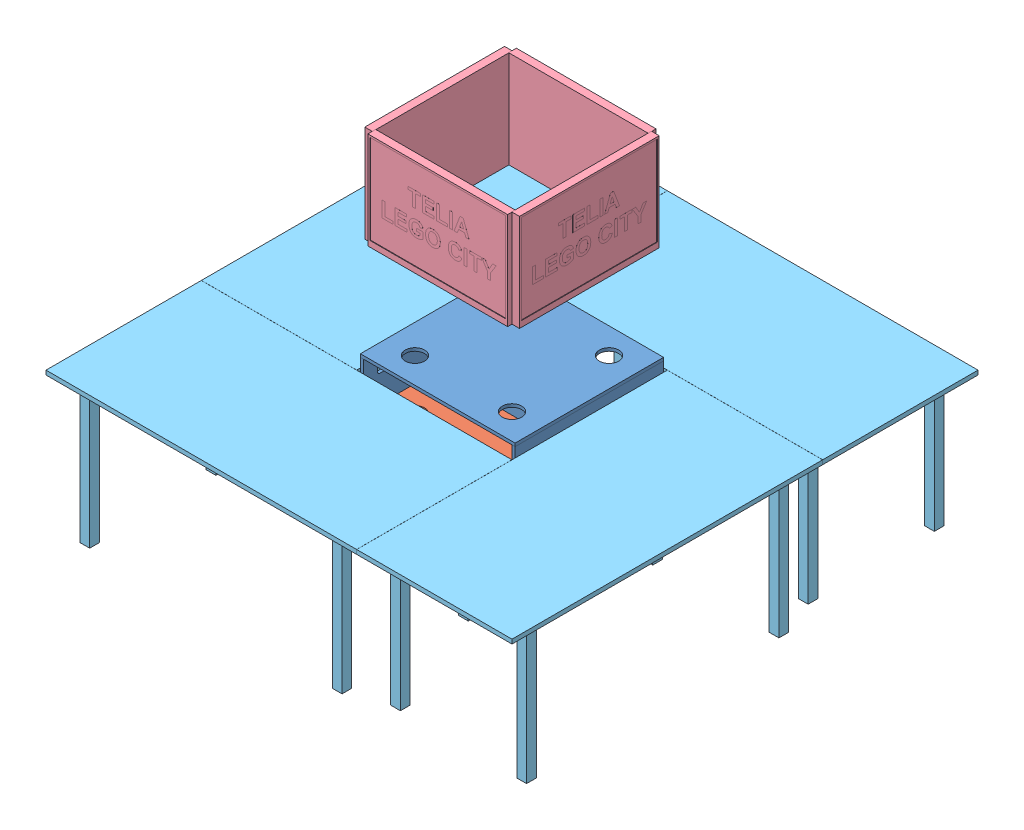
SolidWorks assembly bottom-assembly, configuration Default. Lengths in mm.
Overall size (2400.5 1797 2400.5).
16 component instances, 5 part files, 44 mates.
Components (placement in the parent):
- table-board-1: table-board [Side boards] at (59.7542 3.6875 0) x (0 -1 0) z (0 0 1) size (765 16 765)
- table-board-2: table-board [Middle board] at (458.2542 3.6875 -8) x (1 0 0) z (0 -1 0) size (765 16 765)
- table-board-3: table-board [Side boards] at (840.7542 3.6875 0) x (0 -1 0) z (0 0 1) size (765 16 765)
- table-board-4: table-board [Wide with holes] at (474.2542 386.1875 0) size (797 16 765)
- table-board-5: table-board [Wide] at (474.2542 -394.8125 0) size (797 16 765)
- table-shelf-1: table-shelf [WIth holes] at (458.2542 -136.58 195.25) size (765 16 374.5)
- computer-1: computer [Default] at (446.7489 -378.8125 -241.6898) x (-1 0 0) z (0 0 -1) size (490 460 190)
- table-shelf-2: table-shelf [WIth holes] at (458.2542 127.9549 195.25) size (765 16 374.5)
- tv-1: tv [Default] at (458.2542 1152.1875 342.5) x (1 0 0) z (0 -1 0) size (720 40 500)
- tv-3: tv [Default] at (816.7542 1152.1875 0) x (0 0 -1) z (0 -1 0) size (720 40 500)
- tv-5: tv [Default] at (458.2542 1152.1875 -342.5) x (-1 0 0) z (0 -1 0) size (720 40 500)
- tv-7: tv [Default] at (99.7542 1152.1875 0) x (0 0 1) z (0 -1 0) size (720 40 500)
- table-section-1: table-section [Default] at (-341.9958 315.1875 -400.25) x (0 0 1) z (-1 0 0) size (1600 732 800)
- table-section-2: table-section [Default] at (58.0042 315.1875 800.25) size (1600 732 800)
- table-section-4: table-section [Default] at (1258.5042 315.1875 400.25) x (0 0 -1) z (1 0 0) size (1600 732 800)
- table-section-5: table-section [Default] at (858.5042 315.1875 -800.25) x (-1 0 0) z (0 0 -1) size (1600 732 800)
Mates (geometry in assembly coordinates):
- Coincident5: coincident aligned: plane of table-board-2 through (75.7542 386.1875 8) normal (0 1 0); plane of table-board-3 through (856.7542 386.1875 -382.5) normal (0 1 0)
- Coincident8: coincident anti-aligned: plane of table-board-2 through (840.7542 386.1875 8) normal (1 0 0); plane of table-board-3 through (840.7542 3.6875 0) normal (-1 0 0)
- Coincident9: coincident anti-aligned: plane of table-board-2 through (75.7542 386.1875 8) normal (0 1 0); plane of table-board-4 through (474.2542 386.1875 0) normal (0 -1 0)
- Coincident10: coincident aligned: plane of table-board-3 through (856.7542 3.6875 0) normal (1 0 0); plane of table-board-4 through (856.7542 402.1875 -382.5) normal (1 0 0)
- Coincident11: coincident aligned: plane of table-board-3 through (856.7542 386.1875 382.5) normal (0 0 1); plane of table-board-4 through (91.7542 402.1875 382.5) normal (0 0 1)
- Coincident12: coincident anti-aligned: plane of table-board-2 through (75.7542 -378.8125 8) normal (0 -1 0); plane of table-board-5 through (474.2542 -378.8125 0) normal (0 1 0)
- Coincident13: coincident aligned: plane of table-board-3 through (856.7542 386.1875 382.5) normal (0 0 1); plane of table-board-5 through (91.7542 -378.8125 382.5) normal (0 0 1)
- Coincident14: coincident aligned: plane of table-board-3 through (856.7542 3.6875 0) normal (1 0 0); plane of table-board-5 through (856.7542 -378.8125 -382.5) normal (1 0 0)
- Coincident15: coincident anti-aligned: plane of table-board-1 through (75.7542 386.1875 -382.5) normal (0 1 0); plane of table-board-4 through (474.2542 386.1875 0) normal (0 -1 0)
- Coincident16: coincident anti-aligned: plane of table-board-1 through (75.7542 3.6875 0) normal (1 0 0); plane of table-board-2 through (75.7542 386.1875 8) normal (-1 0 0)
- Coincident17: coincident aligned: plane of table-board-1 through (75.7542 386.1875 382.5) normal (0 0 1); plane of table-board-4 through (91.7542 402.1875 382.5) normal (0 0 1)
- Width1: width aligned: plane of table-board-5 through (91.7542 -378.8125 382.5) normal (0 0 1); plane of table-board-5 through (91.7542 -378.8125 -382.5) normal (0 0 -1); plane of table-board-2 through (458.2542 3.6875 8) normal (0 0 1); plane of table-board-2 through (458.2542 3.6875 -8) normal (0 0 -1)
- Coincident18: coincident anti-aligned: plane of table-board-1 through (75.7542 3.6875 0) normal (1 0 0); plane of table-shelf-1 through (75.7542 -120.58 8) normal (-1 0 0)
- Coincident19: coincident aligned: plane of table-board-1 through (75.7542 386.1875 382.5) normal (0 0 1); plane of table-shelf-1 through (75.7542 -120.58 382.5) normal (0 0 1)
- Coincident20: coincident anti-aligned: plane of table-board-5 through (474.2542 -378.8125 0) normal (0 1 0); plane of computer-1 through (446.7489 -378.8125 -241.6898) normal (0 -1 0)
- Coincident21: coincident anti-aligned: plane of table-board-1 through (75.7542 3.6875 0) normal (1 0 0); plane of table-shelf-2 through (75.7542 143.9549 8) normal (-1 0 0)
- Coincident22: coincident aligned: plane of table-board-1 through (75.7542 386.1875 382.5) normal (0 0 1); plane of table-shelf-2 through (75.7542 143.9549 382.5) normal (0 0 1)
- Width3: width aligned: plane of table-board-5 through (474.2542 -378.8125 0) normal (0 1 0); plane of table-board-4 through (474.2542 402.1875 0) normal (0 1 0); plane of table-shelf-1 through (458.2542 -120.58 195.25) normal (0 1 0); plane of table-shelf-2 through (458.2542 143.9549 195.25) normal (0 1 0)
- Coincident23: coincident anti-aligned: plane of assembly through (0 902.1875 0) normal (0 1 0); plane of tv-1 through (98.2542 902.1875 382.5) normal (0 -1 0)
- Width4: width aligned: plane of table-board-4 through (856.7542 402.1875 -382.5) normal (1 0 0); plane of table-board-4 through (59.7542 386.1875 0) normal (-1 0 0); plane of tv-1 through (818.2542 1402.1875 382.5) normal (1 0 0); plane of tv-1 through (98.2542 1402.1875 382.5) normal (-1 0 0)
- Coincident24: coincident aligned: plane of table-board-4 through (91.7542 402.1875 382.5) normal (0 0 1); plane of tv-1 through (458.2542 1152.1875 382.5) normal (0 0 1)
- Coincident25: coincident anti-aligned: plane of table-board-4 through (474.2542 402.1875 0) normal (0 1 0); plane of ? through (651.0115 402.1875 366.5) normal (0 -1 0)
- Width5: width aligned: plane of table-board-4 through (91.7542 402.1875 -382.5) normal (0 0 -1); plane of table-board-4 through (91.7542 402.1875 382.5) normal (0 0 1); plane of ? through (651.0115 885.1875 -366.5) normal (0 0 -1); plane of ? through (651.0115 885.1875 366.5) normal (0 0 1)
- Coincident26: coincident anti-aligned: plane of assembly through (0 902.1875 0) normal (0 1 0); plane of tv-3 through (856.7542 902.1875 360) normal (0 -1 0)
- Width7: width aligned: plane of table-board-4 through (91.7542 402.1875 -382.5) normal (0 0 -1); plane of table-board-4 through (91.7542 402.1875 382.5) normal (0 0 1); plane of tv-3 through (856.7542 1402.1875 -360) normal (0 0 -1); plane of tv-3 through (856.7542 1402.1875 360) normal (0 0 1)
- Coincident28: coincident aligned: plane of table-board-4 through (856.7542 402.1875 -382.5) normal (1 0 0); plane of tv-3 through (856.7542 1152.1875 0) normal (1 0 0)
- Coincident30: coincident anti-aligned: plane of assembly through (0 902.1875 0) normal (0 1 0); plane of tv-5 through (818.2542 902.1875 -382.5) normal (0 -1 0)
- Width8: width aligned: plane of table-board-4 through (856.7542 402.1875 -382.5) normal (1 0 0); plane of table-board-4 through (59.7542 386.1875 0) normal (-1 0 0); plane of tv-5 through (98.2542 1402.1875 -382.5) normal (-1 0 0); plane of tv-5 through (818.2542 1402.1875 -382.5) normal (1 0 0)
- Coincident31: coincident aligned: plane of table-board-4 through (91.7542 402.1875 -382.5) normal (0 0 -1); plane of tv-5 through (458.2542 1152.1875 -382.5) normal (0 0 -1)
- Coincident33: coincident anti-aligned: plane of assembly through (0 902.1875 0) normal (0 1 0); plane of tv-7 through (59.7542 902.1875 -360) normal (0 -1 0)
- Width10: width aligned: plane of table-board-4 through (91.7542 402.1875 -382.5) normal (0 0 -1); plane of table-board-4 through (91.7542 402.1875 382.5) normal (0 0 1); plane of tv-7 through (59.7542 1402.1875 360) normal (0 0 1); plane of tv-7 through (59.7542 1402.1875 -360) normal (0 0 -1)
- Coincident34: coincident aligned: plane of table-board-4 through (59.7542 386.1875 0) normal (-1 0 0); plane of tv-7 through (59.7542 1152.1875 0) normal (-1 0 0)
- Coincident35: coincident aligned: plane of table-board-5 through (474.2542 -394.8125 0) normal (0 -1 0); plane of table-section-1 through (-341.9958 -394.8125 -400.5) normal (0 -1 0)
- Coincident36: coincident aligned: plane of table-board-5 through (474.2542 -394.8125 0) normal (0 -1 0); plane of table-section-2 through (58.0042 -394.8125 800) normal (0 -1 0)
- Coincident38: coincident aligned: plane of table-section-1 through (-741.9958 337.1875 -1200.5) normal (-1 0 0); plane of table-section-2 through (-741.9958 337.1875 400) normal (-1 0 0)
- Distance1: distance = 0.5 mm anti-aligned: plane of table-section-1 through (58.0042 337.1875 399.75) normal (0 0 1); plane of table-section-2 through (-741.9958 337.1875 400.25) normal (0 0 -1)
- Coincident40: coincident aligned: plane of table-board-5 through (474.2542 -394.8125 0) normal (0 -1 0); plane of table-section-4 through (1258.5042 -394.8125 400) normal (0 -1 0)
- Coincident41: coincident aligned: plane of table-section-2 through (-741.9958 337.1875 1200) normal (0 0 1); plane of table-section-4 through (858.5042 337.1875 1200) normal (0 0 1)
- Distance2: distance = 0.5 mm anti-aligned: plane of table-section-2 through (858.0042 337.1875 400.25) normal (1 0 0); plane of table-section-4 through (858.5042 337.1875 1200.25) normal (-1 0 0)
- Coincident43: coincident aligned: plane of table-board-5 through (474.2542 -394.8125 0) normal (0 -1 0); plane of table-section-5 through (858.5042 -394.8125 -800) normal (0 -1 0)
- Coincident44: coincident aligned: plane of table-section-4 through (1658.5042 337.1875 1200) normal (1 0 0); plane of table-section-5 through (1658.5042 337.1875 -400) normal (1 0 0)
- Distance3: distance = 0.5 mm anti-aligned: plane of table-section-4 through (858.5042 337.1875 -399.75) normal (0 0 -1); plane of table-section-5 through (1658.5042 337.1875 -400.25) normal (0 0 1)
- Width11: width anti-aligned: plane of table-section-2 through (-741.9958 337.1875 400) normal (0 0 -1); plane of table-section-5 through (1658.5042 337.1875 -400) normal (0 0 1); plane of table-board-4 through (91.7542 402.1875 382.5) normal (0 0 1); plane of table-board-4 through (91.7542 402.1875 -382.5) normal (0 0 -1)
- Width12: width anti-aligned: plane of table-section-4 through (858.5042 337.1875 1200) normal (-1 0 0); plane of table-section-1 through (58.0042 337.1875 -1200.5) normal (1 0 0); plane of table-board-4 through (856.7542 402.1875 -382.5) normal (1 0 0); plane of table-board-4 through (59.7542 386.1875 0) normal (-1 0 0)
